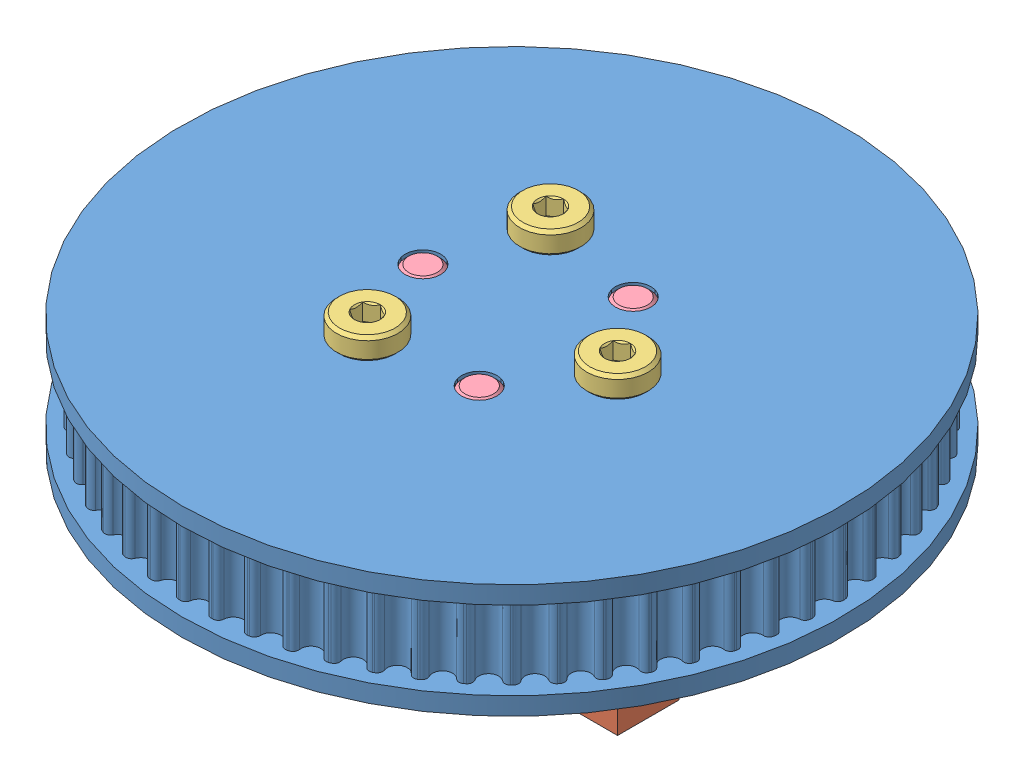
SolidWorks assembly Outrigged Large Pulley Assem, configuration Default. Lengths in mm.
Overall size (58.88 27.2 58.88).
10 component instances, 4 part files, 9 mates.
Components (placement in the parent):
- Outrigged Pulley Big-1: Outrigged Pulley Big [Default] at origin size (58.88 10.97 58.88)
- m3 Square Nut-1: m3 Square Nut [Default] at (9.4437 -18.6625 0) size (5.5 2.5 5.5)
- 92855A317_TYPE 18-8 SS LOW PROFILE SOCKET CAP SCREW-1: 92855A317_TYPE 18-8 SS LOW PROFILE SOCKET CAP SCREW [92855A317] at (9.4437 -19.9125 0) x (1 0 0) z (0 -1 0) size (5.5 5.5 27.2)
- Dowel 98381A471_ALLOY STEEL DOWEL PIN-1: Dowel 98381A471_ALLOY STEEL DOWEL PIN [98381A471] at (-7.9375 -1.2625 0) x (0 -1 0) z (-1 0 0) size (12.7 3.17 3.17)
- Dowel 98381A471_ALLOY STEEL DOWEL PIN-2: Dowel 98381A471_ALLOY STEEL DOWEL PIN [98381A471] at (3.9688 -1.2625 -6.8741) x (0 -1 0) z (0.5 0 -0.866025) size (12.7 3.17 3.17)
- Dowel 98381A471_ALLOY STEEL DOWEL PIN-3: Dowel 98381A471_ALLOY STEEL DOWEL PIN [98381A471] at (3.9688 -1.2625 6.8741) x (0 -1 0) z (0.5 0 0.866025) size (12.7 3.17 3.17)
- 92855A317_TYPE 18-8 SS LOW PROFILE SOCKET CAP SCREW-2: 92855A317_TYPE 18-8 SS LOW PROFILE SOCKET CAP SCREW [92855A317] at (-4.7219 -19.9125 8.1785) x (-0.5 0 0.866025) z (0 -1 0) size (5.5 5.5 27.2)
- 92855A317_TYPE 18-8 SS LOW PROFILE SOCKET CAP SCREW-3: 92855A317_TYPE 18-8 SS LOW PROFILE SOCKET CAP SCREW [92855A317] at (-4.7219 -19.9125 -8.1785) x (-0.5 0 -0.866025) z (0 -1 0) size (5.5 5.5 27.2)
- m3 Square Nut-2: m3 Square Nut [Default] at (-4.7219 -18.6625 8.1785) x (-0.5 0 0.866025) z (-0.866025 0 -0.5) size (5.5 2.5 5.5)
- m3 Square Nut-3: m3 Square Nut [Default] at (-4.7219 -18.6625 -8.1785) x (-0.5 0 -0.866025) z (0.866025 0 -0.5) size (5.5 2.5 5.5)
Mates (geometry in assembly coordinates):
- Concentric1: concentric aligned: cylinder of Outrigged Pulley Big-1 through (9.4437 -5.0875 0) axis (0 1 0) radius 1.5; cylinder of m3 Square Nut-1 through (9.4437 -17.4125 0) axis (0 1 0) radius 1.25
- Coincident1: coincident aligned: plane of m3 Square Nut-1 through (9.4437 -18.6625 0) normal (0 0 1)
- Distance1: distance = 25 mm anti-aligned: plane of Outrigged Pulley Big-1 through (0 5.0875 0) normal (0 1 0); plane of m3 Square Nut-1 through (9.4437 -19.9125 0) normal (0 -1 0)
- Concentric2: concentric anti-aligned: cylinder of Outrigged Pulley Big-1 through (9.4437 -5.0875 0) axis (0 1 0) radius 1.5; line of 92855A317_TYPE 18-8 SS LOW PROFILE SOCKET CAP SCREW-1 through (24.5947 9.4437 5.0875) axis (0 0 -1)
- Coincident3: coincident anti-aligned: plane of Outrigged Pulley Big-1 through (0 5.0875 0) normal (0 1 0); plane of 92855A317_TYPE 18-8 SS LOW PROFILE SOCKET CAP SCREW-1 through (9.4437 5.0875 0) normal (0 -1 0)
- Coincident4: coincident: plane of 92855A317_TYPE 18-8 SS LOW PROFILE SOCKET CAP SCREW-1 through (9.4437 -19.9125 0) normal (0 0 1)
- Concentric3: concentric anti-aligned: cylinder of Outrigged Pulley Big-1 through (-7.9375 -5.0875 0) axis (0 1 0) radius 1.5875; cylinder of Dowel 98381A471_ALLOY STEEL DOWEL PIN-1 through (-7.9375 5.0875 0) axis (0 -1 0) radius 1.5875
- Coincident5: coincident aligned: plane of Outrigged Pulley Big-1 through (0 5.0875 0) normal (0 1 0); plane of Dowel 98381A471_ALLOY STEEL DOWEL PIN-1 through (-7.9375 5.0875 0) normal (0 1 0)
- Coincident6: coincident: plane of Dowel 98381A471_ALLOY STEEL DOWEL PIN-1 through (-7.9375 -1.2625 0) normal (0 0 1)
